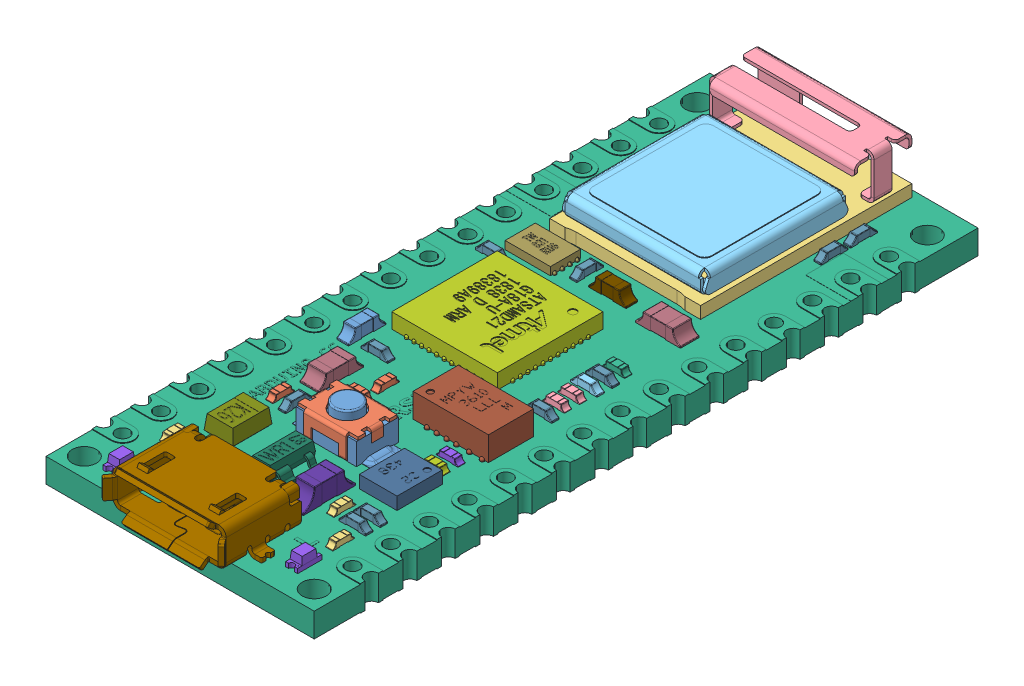
SolidWorks assembly Arduino Nano 33 IoT, configuration Default. Lengths in mm.
Overall size (17.78 5.55 45.32).
46 component instances, 26 part files, 0 mates.
Components (placement in the parent):
- Arduino Nano 33 IoT.stp-1: Arduino Nano 33 IoT.stp [Default] at origin size (17.78 5.55 45.32)
  - Reser Button.stp-1: Reser Button.stp [Default] at (0 0.8 10.91) size (5.21 2.15 3)
    - User Library-arduino_nano_reset core.stp-1: User Library-arduino_nano_reset core.stp [Default] at origin size (5.21 2.15 2.8)
    - User Library-arduino_nano_reset shell.stp-1: User Library-arduino_nano_reset shell.stp [Default] at (0 1.65 0) x (0 0 1) z (-1 0 0) size (3 1.65 4)
  - NINA-W102 Module.stp-1: NINA-W102 Module.stp [Default] at (0 0.85 -14.5) x (0 0 -1) z (1 0 0) size (14 3.85 10)
    - NINA-W102 Body.stp-1: NINA-W102 Body.stp [Default] at origin size (14 0.85 10)
    - NINA-W102 Antenna.stp-1: NINA-W102 Antenna.stp [Default] at (7 0.8 0) size (3.8 3 10)
    - NINA-W102 Cover.stp-1: NINA-W102 Cover.stp [Default] at (-1.7 2 0) x (0 0 1) z (-1 0 0) size (9.5 1.45 9.6)
  - Nano_33IoT Body.stp-1: Nano_33IoT Body.stp [Default] at origin size (17.78 1.75 44)
  - atmegaSAMD21.stp-1: atmegaSAMD21.stp [Default] at (-1.21 0.82 -0.24) x (0 0 -1) z (1 0 0) size (7.23 1.02 7.23)
  - HSMG-C190 LED.stp-1: HSMG-C190 LED.stp [Default] at (5.79 0.8 19.6) x (0 0 1) z (-1 0 0) size (1.6 0.8 0.8)
  - HSMG-C190 LED.stp-2: HSMG-C190 LED.stp [Default] at (-5.81 0.8 20.1) x (0 0 1) z (-1 0 0) size (1.6 0.8 0.8)
  - ZX62-AB-5PA Micro USB.stp-1: ZX62-AB-5PA Micro USB.stp [Default] at (0 2.22 19.2) size (8.81 3.08 5.64)
  - LSM6DS3 Accelerometer.stp-1: LSM6DS3 Accelerometer.stp [Default] at (4.6275 0.82 12) x (-1 0 0) z (0 0 -1) size (2.5 0.85 3)
  - MPM3610 Step-Down Module.stp-1: MPM3610 Step-Down Module.stp [Default] at (3.69 1.65 6.25) x (0 0 1) z (-1 0 0) size (3.3 1.65 5.15)
  - ATECC608A No Lead Crypto Auth.stp-1: ATECC608A No Lead Crypto Auth.stp [Default] at (-4.035 0.8 -6.08) x (0 0 -1) z (1 0 0) size (2 0.55 3.3)
  - CL21A226MQCLQNC Capacitor.stp-1: CL21A226MQCLQNC Capacitor.stp [Default] at (4.44 1.225 -5.85) x (-1 0 0) z (0 0 -1) size (3 0.85 1.25)
  - TDK C1005 Capacitor.stp-1: TDK C1005 Capacitor.stp [Default] at (5.5825 1.05 -15.55) x (0 0 -1) z (1 0 0) size (1.8 0.5 0.5)
  - TDK C1005 Capacitor.stp-2: TDK C1005 Capacitor.stp [Default] at (5.5825 1.05 -17.5125) x (0 0 -1) z (1 0 0) size (1.8 0.5 0.5)
  - CL21A226MQCLQNC Capacitor.stp-2: CL21A226MQCLQNC Capacitor.stp [Default] at (-4.11 1.225 7.8375) x (0 0 1) z (-1 0 0) size (3 0.85 1.25)
  - TDK C1005 Capacitor.stp-3: TDK C1005 Capacitor.stp [Default] at (5.385 1.05 15.7375) size (1.8 0.5 0.5)
  - TDK C1005 Capacitor.stp-4: TDK C1005 Capacitor.stp [Default] at (5.385 1.05 14.7625) size (1.8 0.5 0.5)
  - PRTR5V0U2X Protection Diode.stp-1: PRTR5V0U2X Protection Diode.stp [Default] at (-0.41 1.45 14.77) x (0 0 -1) z (1 0 0) size (3 1.1 2.5)
  - PMEG6020AELR Diode.stp-1: PMEG6020AELR Diode.stp [Default] at (-4.06 0.85 14.1) x (0 0 1) z (-1 0 0) size (3.3 1.11 1.9)
  - C0805C472KDRACTU Capacitor.stp-1: C0805C472KDRACTU Capacitor.stp [Default] at (2.415 1.425 15.1325) x (0 0 1) z (-1 0 0) size (3.5 1.25 1.25)
  - TDK C1005 Capacitor.stp-5: TDK C1005 Capacitor.stp [Default] at (-1.52 1.05 -6.46) x (0 0 -1) z (1 0 0) size (1.8 0.5 0.5)
  - BLM18PG471SN1D Ferrite Bead.stp-1: BLM18PG471SN1D Ferrite Bead.stp [Default] at (0.61 1.2 -6.1) x (-1 0 0) z (0 0 -1) size (2.5 0.8 0.8)
  - TDK C1005 Capacitor.stp-6: TDK C1005 Capacitor.stp [Default] at (-5.66 1.05 -4.35) x (-1 0 0) z (0 0 -1) size (1.8 0.5 0.5)
  - TDK C1005 Capacitor.stp-7: TDK C1005 Capacitor.stp [Default] at (-3.64 1.05 10.73) x (0 0 1) z (-1 0 0) size (1.8 0.5 0.5)
  - TDK C1005 Capacitor.stp-8: TDK C1005 Capacitor.stp [Default] at (-3.79 1.05 5.1) size (1.8 0.5 0.5)
  - GRM188R61E475KE11D Capacitor.stp-1: GRM188R61E475KE11D Capacitor.stp [Default] at (-5.59 1.2 4.4) x (0 0 1) z (-1 0 0) size (2.5 0.8 0.8)
  - RC0402FR-07100KL Resistor.stp-1: RC0402FR-07100KL Resistor.stp [Default] at (-2.01 1 8.1625) x (-1 0 0) z (0 0 -1) size (1.48 0.48 0.64)
  - RC0402FR-07100KL Resistor.stp-2: RC0402FR-07100KL Resistor.stp [Default] at (-1.6975 1 6.7125) x (0 0 1) z (-1 0 0) size (1.48 0.48 0.64)
  - RC0402FR-07330RL Resistor.stp-1: RC0402FR-07330RL Resistor.stp [Default] at (-5.81 1 16.6) x (0 0 1) z (-1 0 0) size (1.48 0.48 0.64)
  - RC0402FR-07330RL Resistor.stp-2: RC0402FR-07330RL Resistor.stp [Default] at (5.8025 1 17.2) x (0 0 1) z (-1 0 0) size (1.48 0.48 0.64)
  - RC0402FR-07330RL Resistor.stp-3: RC0402FR-07330RL Resistor.stp [Default] at (3.915 1 15.2325) x (0 0 1) z (-1 0 0) size (1.48 0.48 0.64)
  - TDK C1005 Capacitor.stp-9: TDK C1005 Capacitor.stp [Default] at (5.09 1.05 3.1) x (-1 0 0) z (0 0 -1) size (1.8 0.5 0.5)
  - RC0402FR-074K7L Resistor.stp-1: RC0402FR-074K7L Resistor.stp [Default] at (5.09 1 2.1) size (1.48 0.48 0.64)
  - RC0402FR-074K7L Resistor.stp-2: RC0402FR-074K7L Resistor.stp [Default] at (5.09 1 1.1) x (-1 0 0) z (0 0 -1) size (1.48 0.48 0.64)
  - GRM155R61E105KA12D Capacitor.stp-1: GRM155R61E105KA12D Capacitor.stp [Default] at (5.09 1.05 0.1) size (1.8 0.5 0.5)
  - TDK C1005 Capacitor.stp-10: TDK C1005 Capacitor.stp [Default] at (5.09 1.05 -0.9) x (-1 0 0) z (0 0 -1) size (1.8 0.5 0.5)
  - RC0402FR-071KL Resistor.stp-1: RC0402FR-071KL Resistor.stp [Default] at (5.09 1 -1.9) x (-1 0 0) z (0 0 -1) size (1.48 0.48 0.64)
  - RC0402FR-07100KL Resistor.stp-3: RC0402FR-07100KL Resistor.stp [Default] at (-5.74 1 -13.5) x (0 0 -1) z (1 0 0) size (1.48 0.48 0.64)
  - RC0402FR-07100KL Resistor.stp-4: RC0402FR-07100KL Resistor.stp [Default] at (-4.64 1 10.73) x (0 0 1) z (-1 0 0) size (1.48 0.48 0.64)
  - AC0402JR-0724KL Resistor.stp-1: AC0402JR-0724KL Resistor.stp [Default] at (4.665 0.985 9.725) size (1.48 0.39 0.56)
  - AC0402JR-0775KL Resistor.stp-1: AC0402JR-0775KL Resistor.stp [Default] at (4.665 0.985 8.725) size (1.48 0.39 0.56)
